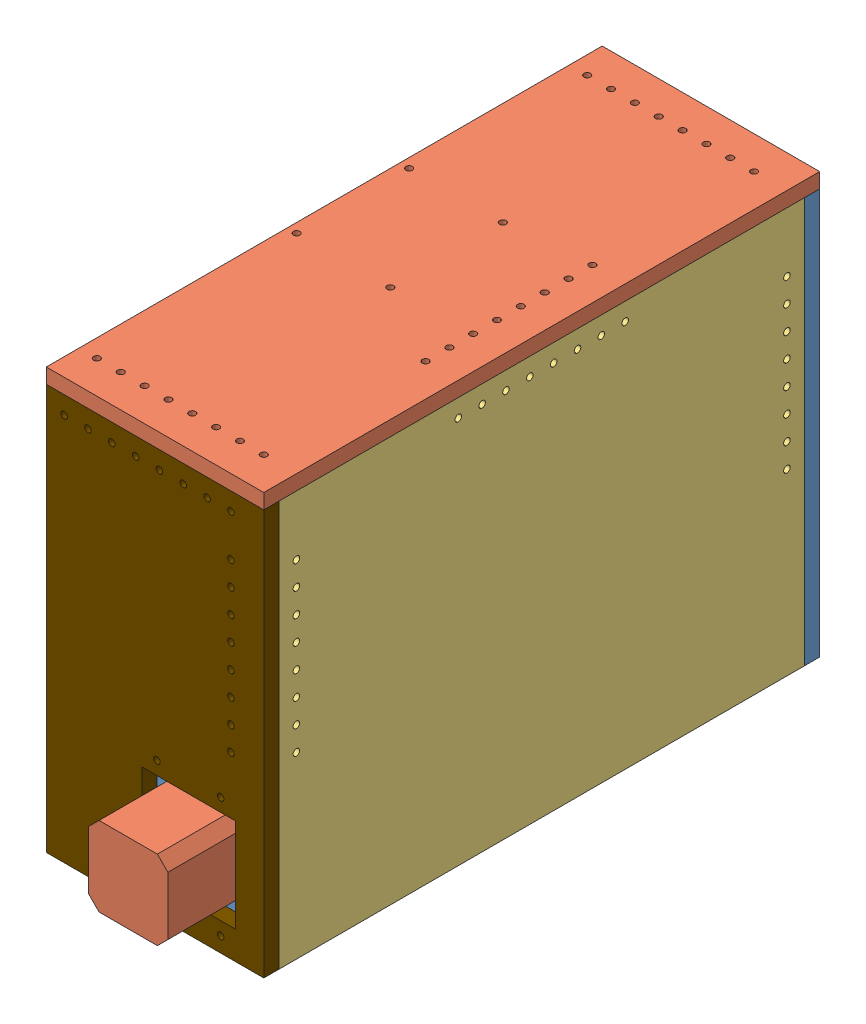
SolidWorks assembly MontagemPlataforma2, configuration Valor predeterminado. Lengths in mm.
Overall size (116 224.23 328.8).
33 component instances, 23 part files, 95 mates.
Components (placement in the parent):
- SuporteMotor-1: SuporteMotor [Valor predeterminado] at (-12.7116 1.7334 80) size (80 80 60)
- motorPasso-1: motorPasso [Valor predeterminado] at (-12.7116 1.7334 104.15) x (-1 0 0) z (0 -1 0) size (42.3 68.3 42.3)
- acoplador-1: acoplador [Valor predeterminado] at (-12.7116 1.7334 69.5) x (0.958308 -0.285739 0) z (0.285739 0.958308 0) size (19 25 19)
- ContraApoioMotor-1: ContraApoioMotor [Valor predeterminado] at (-12.7116 1.7334 -190.5) x (1 0 0) z (0 0 -1) size (80 80 39.5)
- plataforma-1: plataforma [Valor predeterminado] at (-58.7116 10.0216 -65.5) x (1 0 0) z (0 1 0) size (55 220 10)
- suportePlataforma-1: suportePlataforma [Valor predeterminado] at (-58.7116 20.0216 -65.5) x (0 0 1) z (0 1 0) size (190 55 65)
- guia200_5mm-1: guia200_5mm [Valor predeterminado] at (-12.7116 -25.2666 -55.25) x (1 0 0) z (0 -1 0) size (8 280.5 8)
- guia200_5mm-2: guia200_5mm [Valor predeterminado] at (-12.7116 28.7334 -55.25) x (1 0 0) z (0 -1 0) size (8 280.5 8)
- fusoTrapazoidal172_5mm-1: fusoTrapazoidal172_5mm [Valor predeterminado] at (-12.7116 1.7334 -69.25) x (-0.923728 -0.383049 0) z (-0.383049 0.923728 0) size (8.12 256.57 9.26)
- Rolamento-2: Rolamento [Valor predeterminado] at (-12.7116 1.7334 -185.5) size (47.5 27 13)
- RolamentoLinear-1: RolamentoLinear [Valor predeterminado] at (-12.7116 -25.2666 -128.1288) x (0.814438 -0.58025 0) z (0.58025 0.814438 0) size (15 24 15)
- RolamentoLinear-2: RolamentoLinear [Valor predeterminado] at (-12.7116 28.7334 -128.1288) x (1 0 0) z (0 1 0) size (15 24 15)
- corredor-1: corredor [Valor predeterminado] at (-11.7116 1.7334 -140.1288) x (-1 0 0) z (0 0 1) size (63.5 80 35)
- SensorFimdeCurso-1: SensorFimdeCurso [Valor predeterminado] at (-22.9616 27.9849 -179.2725) x (0 -1 0) z (-1 0 0) size (27.68 29.29 6)
- motorPasso para fuso-1: motorPasso para fuso [Valor predeterminado] at (-58.7116 156.8134 -65.5) x (0 0 1) z (1 0 0) size (42.3 44.3 42.3)
- fusoTrapazoidal100_8mm-1: fusoTrapazoidal100_8mm [Valor predeterminado] at (-58.7116 106.1634 -65.5) x (0.966852 0 -0.255339) z (0.255339 0 0.966852) size (8 56.69 8)
- Castanha-1: Castanha [Valor predeterminado] at (-58.7116 88.5216 -65.5) x (1 0 0) z (0 0 -1) size (22 15 22)
- box-1: box [Valor predeterminado] at (-46.3823 57.5484 4.885) size (240.83 240.83 240.83) (hidden)
- Castanha-2: Castanha [Valor predeterminado] at (-12.7116 1.7334 -130.1288) x (1 0 0) z (0 -1 0) size (22 15 22)
- RolamentoLinear-3: RolamentoLinear [Valor predeterminado] at (-58.7116 10.0216 34.5) size (15 24 15)
- RolamentoLinear-4: RolamentoLinear [Valor predeterminado] at (-58.7116 10.0216 -165.5) size (15 24 15)
- guia175.43_8mm-1: guia175.43_8mm [Valor predeterminado] at (-58.7116 69.8484 34.5) x (0.837169 0 0.546944) z (0 1 0) size (8 8 216.23)
- guia175.43_8mm-2: guia175.43_8mm [Valor predeterminado] at (-58.7116 69.8484 -165.5) x (1 0 0) z (0 -1 0) size (8 8 216.23)
- suporteFusoGuiaMotor-1: suporteFusoGuiaMotor [Valor predeterminado] at (-58.7116 172.9634 -65.5) x (0 0 1) z (0 -1 0) size (220 60 20)
- acrilico1-1: acrilico1 [Valor predeterminado] at (-12.7116 1.7334 85) x (-1 0 0) z (0 0 1) size (116 216.23 8)
- acrilico2-2: acrilico2 [Valor predeterminado] at (-30.7116 69.8484 -195.5) x (1 0 0) z (0 0 -1) size (116 216.23 8)
- acrilico3-1: acrilico3 [Valor predeterminado] at (-30.7116 185.9634 -55.25) x (1 0 0) z (0 -1 0) size (116 296.5 8)
- acrilico4-1: acrilico4 [Valor predeterminado] at (27.2884 69.8484 -55.25) x (0 0 1) z (-1 0 0) size (280.5 216.23 8)
- cantoneira-1: cantoneira [Valor predeterminado] at (19.2884 177.9634 -105.25) x (-1 0 0) z (0 0 1) size (15 15 100)
- cantoneira-2: cantoneira [Valor predeterminado] at (15.2884 177.9634 85) x (0 0 -1) z (-1 0 0) size (15 15 100)
- cantoneira-3: cantoneira [Valor predeterminado] at (-84.7116 177.9634 -195.5) x (0 0 1) z (1 0 0) size (15 15 100)
- cantoneira-4: cantoneira [Valor predeterminado] at (19.2884 151.7334 85.0065) x (-1 0 0) z (0 -1 0) size (15 15 100)
- cantoneira-5: cantoneira [Valor predeterminado] at (19.2884 151.7334 -195.5) x (0 0 1) z (0 -1 0) size (15 15 100)
Mates (geometry in assembly coordinates):
- Concêntrico1: concentric: cylinder of SuporteMotor-1 through (-12.7116 1.7334 59) axis (0 0 1) radius 11.02; cylinder of motorPasso-1 through (-12.7116 1.7334 81) axis (0 0 1) radius 11.025
- Coincidente1: coincident: plane of SuporteMotor-1 through (8.4384 22.8834 83) normal (-1 0 0); plane of motorPasso-1 through (8.4384 22.8834 83) normal (1 0 0)
- Coincidente2: coincident: plane of SuporteMotor-1 through (-12.7116 1.7334 83) normal (0 0 1); plane of motorPasso-1 through (-12.7116 1.7334 83) normal (0 0 -1)
- Concêntrico2: concentric: cylinder of motorPasso-1 through (-12.7116 1.7334 57) axis (0 0 1) radius 2.506; cylinder of acoplador-1 through (-12.7116 1.7334 57) axis (0 0 -1) radius 4
- Coincidente4: coincident: plane of motorPasso-1 through (-12.7116 1.7334 57) normal (0 0 -1); plane of acoplador-1 through (-12.7116 1.7334 57) normal (0 0 -1)
- Coincidente8: coincident: plane of SuporteMotor-1 through (-37.7116 41.7334 85) normal (0 1 0); plane of ContraApoioMotor-1 through (-37.7116 41.7334 -195.5) normal (0 1 0)
- Coincidente9: coincident: plane of SuporteMotor-1 through (-37.7116 -38.2666 85) normal (0 -1 0); plane of ContraApoioMotor-1 through (-37.7116 -38.2666 -195.5) normal (0 -1 0)
- Concêntrico7: concentric: cylinder of SuporteMotor-1 through (-12.7116 -25.2666 61) axis (0 0 1) radius 4; cylinder of guia200_5mm-1 through (-12.7116 -25.2666 85) axis (0 0 -1) radius 4
- Concêntrico8: concentric: cylinder of SuporteMotor-1 through (-12.7116 28.7334 61) axis (0 0 1) radius 4; cylinder of guia200_5mm-2 through (-12.7116 28.7334 85) axis (0 0 -1) radius 4
- Coincidente15: coincident: plane of SuporteMotor-1 through (-12.7116 1.7334 85) normal (0 0 1); plane of guia200_5mm-1 through (-12.7116 -25.2666 85) normal (0 0 1)
- Coincidente16: coincident: plane of SuporteMotor-1 through (-12.7116 1.7334 85) normal (0 0 1); plane of guia200_5mm-2 through (-12.7116 28.7334 85) normal (0 0 1)
- Concêntrico9: concentric: cylinder of acoplador-1 through (-12.7116 1.7334 57) axis (0 0 -1) radius 4; cylinder of fusoTrapazoidal172_5mm-1 through (-12.7116 1.7334 57) axis (0 0 -1) radius 4
- Coincidente17: coincident: plane of acoplador-1 through (-12.7116 1.7334 57) normal (0 0 -1); plane of fusoTrapazoidal172_5mm-1 through (-12.7116 1.7334 57) normal (0 0 1)
- Concêntrico10: concentric: cylinder of ContraApoioMotor-1 through (-12.7116 1.7334 -185.5) axis (0 0 -1) radius 4.5; cylinder of Rolamento-2 through (-12.7116 1.7334 -172.5) axis (0 0 -1) radius 7
- Concêntrico11: concentric: cylinder of ContraApoioMotor-1 through (-30.9616 1.7334 -185.5) axis (0 0 -1) radius 2.5; cylinder of Rolamento-2 through (-30.9616 1.7334 -181.5) axis (0 0 -1) radius 2.5
- Coincidente18: coincident: plane of ContraApoioMotor-1 through (-12.7116 1.7334 -185.5) normal (0 0 1); plane of Rolamento-2 through (-30.9616 1.7334 -185.5) normal (0 0 -1)
- Concêntrico12: concentric: cylinder of guia200_5mm-1 through (-12.7116 -25.2666 85) axis (0 0 -1) radius 4; cylinder of RolamentoLinear-1 through (-12.7116 -25.2666 -152.1288) axis (0 0 1) radius 4
- Coincidente19: coincident: plane of RolamentoLinear-1 through (-12.7116 -25.2666 -152.1288) normal (0 0 -1); plane of RolamentoLinear-2 through (-12.7116 28.7334 -152.1288) normal (0 0 -1)
- Coincidente20: coincident: plane of ContraApoioMotor-1 through (-27.7116 33.8734 -173.5) normal (0 -1 0); plane of SensorFimdeCurso-1 through (-24.2116 33.8734 -189.5) normal (0 1 0)
- Coincidente21: coincident: plane of ContraApoioMotor-1 through (-27.7116 32.3734 -173.5) normal (1 0 0); plane of SensorFimdeCurso-1 through (-27.7116 32.3734 -189.5) normal (-1 0 0)
- Coincidente22: coincident: plane of ContraApoioMotor-1 through (-12.7116 1.7334 -185.5) normal (0 0 1); plane of SensorFimdeCurso-1 through (-28.9616 35.1234 -185.5) normal (0 0 -1)
- Concêntrico17: concentric: cylinder of ? through (-58.7116 207.1531 -24) axis (0 -1 0) radius 9; cylinder of ? through (-58.7116 128.7561 -24) axis (0 -1 0) radius 9
- Concêntrico19: concentric: cylinder of motorPasso para fuso-1 through (-58.7116 203.6634 -65.5) axis (0 -1 0) radius 4; cylinder of fusoTrapazoidal100_8mm-1 through (-58.7116 133.6634 -65.5) axis (0 -1 0) radius 4
- Coincidente25: coincident: plane of motorPasso para fuso-1 through (-58.7116 133.6634 -65.5) normal (0 -1 0); plane of fusoTrapazoidal100_8mm-1 through (-58.7116 133.6634 -65.5) normal (0 1 0)
- Concêntrico21: concentric: cylinder of Castanha-1 through (-58.7116 122.4327 -7) axis (0 -1 0) radius 5.1; cylinder of ? through (-58.7116 103.9327 -7) axis (0 1 0) radius 5.105
- Paralelo10: parallel: cylinder of Castanha-1 through (-66.7001 122.4327 -6.5713) axis (0 -1 0) radius 1.75; cylinder of ? through (-66.8516 103.9327 -7) axis (0 1 0) radius 1.75
- Coincidente27: coincident: plane of Castanha-1 through (-58.7116 108.9327 -7) normal (0 -1 0); plane of ? through (-58.7116 108.9327 -7) normal (0 1 0)
- Concêntrico23: concentric: cylinder of ? through (-58.7116 103.9327 -37) axis (0 1 0) radius 7.5; cylinder of RolamentoLinear-3 through (-58.7116 122.9327 -37) axis (0 -1 0) radius 7.5
- Distância9: distance = 5 mm: plane of RolamentoLinear-3 through (-58.7116 98.9327 -37) normal (0 -1 0); plane of ? through (-58.7116 103.9327 -7) normal (0 -1 0)
- Concêntrico26: concentric: cylinder of ? through (-58.7116 103.9327 -24) axis (0 1 0) radius 4; cylinder of ? through (-58.7116 103.9327 -24) axis (0 -1 0) radius 4
- Coincidente31: coincident: plane of ? through (-58.7116 103.9327 -7) normal (0 -1 0); plane of ? through (-58.7116 103.9327 -24) normal (0 1 0)
- Concêntrico27: concentric: cylinder of ? through (-58.7116 103.9327 -24) axis (0 -1 0) radius 4; cylinder of ? through (-58.7116 48.9327 -24) axis (0 -1 0) radius 4
- Concêntrico29: concentric: cylinder of RolamentoLinear-3 through (-58.7116 122.9327 -37) axis (0 -1 0) radius 4; cylinder of ? through (-58.7116 79.0394 -37) axis (0 1 0) radius 4
- Coincidente35: coincident: plane of ? through (-58.7116 53.9327 -24) normal (0 -1 0); plane of ? through (-58.7116 53.9327 -24) normal (0 1 0)
- Concêntrico30: concentric: cylinder of fusoTrapazoidal172_5mm-1 through (-12.7116 1.7334 57) axis (0 0 -1) radius 4; cylinder of corredor-1 through (-12.7116 1.7334 -130.1288) axis (0 0 -1) radius 5.1
- Concêntrico32: concentric: cylinder of RolamentoLinear-2 through (-12.7116 28.7334 -152.1288) axis (0 0 1) radius 7.5; cylinder of corredor-1 through (-12.7116 28.7334 -130.1288) axis (0 0 -1) radius 7.5
- Coincidente40: coincident: plane of motorPasso-1 through (-12.7116 1.7334 125.3) normal (0 0 1); plane of box-1 through (-46.3823 57.5484 125.3) normal (0 0 1)
- Distância10: distance = 2 mm: plane of RolamentoLinear-1 through (-12.7116 -25.2666 -128.1288) normal (0 0 1); plane of corredor-1 through (-11.7116 1.7334 -130.1288) normal (0 0 1)
- Concêntrico34: concentric: cylinder of corredor-1 through (-12.7116 1.7334 -130.1288) axis (0 0 -1) radius 5.1; cylinder of Castanha-2 through (-12.7116 1.7334 -140.1288) axis (0 0 1) radius 5.1
- Concêntrico35: concentric: cylinder of corredor-1 through (-4.7116 1.7334 -155.0786) axis (0 0 1) radius 1.75; cylinder of Castanha-2 through (-4.7116 1.7334 -140.1288) axis (0 0 1) radius 1.75
- Coincidente42: coincident: plane of corredor-1 through (-11.7116 1.7334 -130.1288) normal (0 0 1); plane of Castanha-2 through (-12.7116 1.7334 -130.1288) normal (0 0 -1)
- Coincidente43: coincident: plane of plataforma-1 through (-58.7116 20.0216 -65.5) normal (0 1 0); plane of suportePlataforma-1 through (-58.7116 20.0216 -65.5) normal (0 -1 0)
- Concêntrico40: concentric: cylinder of suportePlataforma-1 through (-58.7116 85.0216 -65.5) axis (0 -1 0) radius 5; cylinder of fusoTrapazoidal100_8mm-1 through (-58.7116 133.6634 -65.5) axis (0 -1 0) radius 4
- Paralelo13: parallel: cylinder of suportePlataforma-1 through (-66.7116 57.0216 -65.5) axis (0 1 0) radius 1.75; cylinder of Castanha-1 through (-58.7116 98.5216 -73.5) axis (0 -1 0) radius 1.75
- Concêntrico44: concentric: circle of suportePlataforma-1; circle of Castanha-1
- Coincidente47: coincident: plane of suportePlataforma-1 through (-58.7116 85.0216 -65.5) normal (0 1 0); plane of Castanha-1 through (-58.7116 85.0216 -65.5) normal (0 -1 0)
- Concêntrico48: concentric: cylinder of suportePlataforma-1 through (-50.7116 57.0216 -65.5) axis (0 1 0) radius 1.75; cylinder of Castanha-1 through (-50.7116 98.5216 -65.5) axis (0 -1 0) radius 1.75
- Concêntrico49: concentric: cylinder of plataforma-1 through (-58.7116 10.0216 34.5) axis (0 1 0) radius 7.5; cylinder of RolamentoLinear-3 through (-58.7116 34.0216 34.5) axis (0 -1 0) radius 7.5
- Concêntrico50: concentric: cylinder of plataforma-1 through (-58.7116 10.0216 -165.5) axis (0 1 0) radius 7.5; cylinder of RolamentoLinear-4 through (-58.7116 34.0216 -165.5) axis (0 -1 0) radius 7.5
- Coincidente50: coincident: plane of plataforma-1 through (-58.7116 10.0216 -65.5) normal (0 -1 0); plane of RolamentoLinear-3 through (-58.7116 10.0216 34.5) normal (0 -1 0)
- Concêntrico51: concentric: cylinder of RolamentoLinear-3 through (-58.7116 34.0216 34.5) axis (0 -1 0) radius 4; cylinder of guia175.43_8mm-1 through (-58.7116 177.9634 34.5) axis (0 -1 0) radius 4
- Concêntrico52: concentric: cylinder of RolamentoLinear-4 through (-58.7116 34.0216 -165.5) axis (0 -1 0) radius 4; cylinder of guia175.43_8mm-2 through (-58.7116 -38.2666 -165.5) axis (0 1 0) radius 4
- Concêntrico57: concentric: circle of SuporteMotor-1; cylinder of acrilico1-1 through (-29.7116 -30.2666 93) axis (0 0 -1) radius 1.75
- Concêntrico58: concentric: cylinder of SuporteMotor-1 through (4.2884 33.7334 85) axis (0 0 -1) radius 1.75; cylinder of acrilico1-1 through (4.2884 33.7334 93) axis (0 0 -1) radius 1.75
- Coincidente57: coincident: plane of SuporteMotor-1 through (-12.7116 1.7334 85) normal (0 0 1); plane of acrilico1-1 through (-12.7116 1.7334 85) normal (0 0 -1)
- Concêntrico60: concentric: cylinder of ContraApoioMotor-1 through (-29.7116 -30.2666 -105.5) axis (0 0 -1) radius 1.75; cylinder of ? through (-29.7116 -30.2666 -115.5) axis (0 0 -1) radius 1.75
- Concêntrico61: concentric: cylinder of ContraApoioMotor-1 through (4.2884 33.7334 -105.5) axis (0 0 -1) radius 1.75; cylinder of ? through (4.2884 33.7334 -115.5) axis (0 0 -1) radius 1.75
- Coincidente59: coincident: plane of ContraApoioMotor-1 through (-12.7116 1.7334 -115.5) normal (0 0 -1); plane of ? through (-12.7116 1.7334 -115.5) normal (0 0 1)
- Coincidente68: coincident: plane of acrilico3-1 through (-30.7116 177.9634 -55.25) normal (0 -1 0); plane of acrilico4-1 through (19.2884 177.9634 -195.5) normal (0 1 0)
- Coincidente69: coincident: plane of acrilico3-1 through (27.2884 177.9634 93) normal (1 0 0); plane of acrilico4-1 through (27.2884 69.8484 -55.25) normal (1 0 0)
- Coincidente73: coincident: plane of acrilico1-1 through (-12.7116 1.7334 85) normal (0 0 -1); plane of cantoneira-2 through (-84.7116 177.9634 85) normal (0 0 1)
- Coincidente74: coincident: plane of acrilico3-1 through (-30.7116 177.9634 -55.25) normal (0 -1 0); plane of cantoneira-2 through (-84.7116 177.9634 85) normal (0 1 0)
- Coincidente77: coincident: plane of acrilico3-1 through (-30.7116 177.9634 -55.25) normal (0 -1 0); plane of cantoneira-3 through (15.2884 177.9634 -195.5) normal (0 1 0)
- Coincidente79: coincident: plane of acrilico4-1 through (19.2884 69.8484 -55.25) normal (-1 0 0); plane of cantoneira-4 through (19.2884 51.7334 85.0065) normal (1 0 0)
- Coincidente83: coincident: plane of acrilico4-1 through (19.2884 69.8484 -55.25) normal (-1 0 0); plane of cantoneira-5 through (19.2884 51.7334 -195.5) normal (1 0 0)
- Coincidente89: coincident: plane of acrilico2-2 through (-30.7116 69.8484 -203.5) normal (0 0 -1); plane of acrilico3-1 through (-88.7116 177.9634 -203.5) normal (0 0 -1)
- Coincidente90: coincident: plane of acrilico2-2 through (-30.7116 69.8484 -195.5) normal (0 0 1); plane of cantoneira-3 through (15.2884 177.9634 -195.5) normal (0 0 -1)
- Concêntrico62: concentric: circle of acrilico3-1; cylinder of cantoneira-3 through (-79.2116 273.9634 -186) axis (0 -1 0) radius 1.75
- Concêntrico63: concentric: circle of acrilico2-2; cylinder of cantoneira-3 through (-79.2116 168.4634 -291.5) axis (0 0 1) radius 1.75
- Coincidente91: coincident: plane of motorPasso para fuso-1 through (-79.8616 135.6634 -86.65) normal (0 0 -1); plane of suporteFusoGuiaMotor-1 through (-79.8616 167.9634 -86.65) normal (0 0 1)
- Coincidente92: coincident: plane of motorPasso para fuso-1 through (-79.8616 135.6634 -86.65) normal (-1 0 0); plane of suporteFusoGuiaMotor-1 through (-79.8616 167.9634 -86.65) normal (1 0 0)
- Concêntrico64: concentric: cylinder of plataforma-1 through (-81.2116 20.0216 24.5) axis (0 -1 0) radius 2; cylinder of suportePlataforma-1 through (-81.2116 20.0216 24.5) axis (0 1 0) radius 2
- Concêntrico65: concentric: cylinder of plataforma-1 through (-36.2116 20.0216 24.5) axis (0 -1 0) radius 2; cylinder of suportePlataforma-1 through (-36.2116 20.0216 24.5) axis (0 1 0) radius 2
- Concêntrico66: concentric: cylinder of acrilico4-1 through (17.2884 146.2334 -186) axis (1 0 0) radius 1.75; cylinder of cantoneira-5 through (115.2884 146.2334 -186) axis (-1 0 0) radius 1.75
- Concêntrico68: concentric: circle of cantoneira-5; circle of acrilico4-1
- Concêntrico69: concentric: circle of acrilico2-2; cylinder of cantoneira-5 through (9.7884 146.2334 -291.5) axis (0 0 1) radius 1.75
- Concêntrico70: concentric: cylinder of guia175.43_8mm-1 through (-58.7116 177.9634 34.5) axis (0 -1 0) radius 4; cylinder of suporteFusoGuiaMotor-1 through (-58.7116 157.9634 34.5) axis (0 1 0) radius 8
- Concêntrico71: concentric: cylinder of guia175.43_8mm-2 through (-58.7116 -38.2666 -165.5) axis (0 1 0) radius 4; cylinder of suporteFusoGuiaMotor-1 through (-58.7116 157.9634 -165.5) axis (0 1 0) radius 8
- Coincidente95: coincident: plane of guia175.43_8mm-1 through (-58.7116 177.9634 34.5) normal (0 1 0); plane of suporteFusoGuiaMotor-1 through (-58.7116 177.9634 -65.5) normal (0 1 0)
- Coincidente96: coincident: plane of guia175.43_8mm-2 through (-58.7116 177.9634 -165.5) normal (0 1 0); plane of suporteFusoGuiaMotor-1 through (-58.7116 177.9634 -65.5) normal (0 1 0)
- Concêntrico72: concentric: cylinder of suporteFusoGuiaMotor-1 through (-83.7116 177.9634 -35.5) axis (0 -1 0) radius 1.75; circle of acrilico3-1
- Concêntrico73: concentric: cylinder of suporteFusoGuiaMotor-1 through (-83.7116 177.9634 -95.5) axis (0 -1 0) radius 1.75; circle of acrilico3-1
- Coincidente98: coincident: plane of suporteFusoGuiaMotor-1 through (-58.7116 177.9634 -65.5) normal (0 1 0); plane of acrilico3-1 through (-30.7116 177.9634 -55.25) normal (0 -1 0)
- Coincidente99: coincident: plane of motorPasso para fuso-1 through (-58.7116 177.9634 -65.5) normal (0 1 0); plane of suporteFusoGuiaMotor-1 through (-58.7116 177.9634 -65.5) normal (0 1 0)
- Concêntrico74: concentric: cylinder of acrilico3-1 through (9.7884 277.9634 -99.75) axis (0 -1 0) radius 1.75; cylinder of cantoneira-1 through (9.7884 273.9634 -99.75) axis (0 -1 0) radius 1.75
- Concêntrico75: concentric: cylinder of acrilico4-1 through (119.2884 168.4634 -99.75) axis (-1 0 0) radius 1.75; cylinder of cantoneira-1 through (115.2884 168.4634 -99.75) axis (-1 0 0) radius 1.75
- Concêntrico76: concentric: cylinder of acrilico3-1 through (-79.2116 277.9634 75.5) axis (0 -1 0) radius 1.75; cylinder of cantoneira-2 through (-79.2116 273.9634 75.5) axis (0 -1 0) radius 1.75
- Concêntrico77: concentric: circle of acrilico3-1; cylinder of cantoneira-2 through (-66.4973 273.9634 75.5) axis (0 -1 0) radius 1.75
- Concêntrico78: concentric: cylinder of acrilico1-1 through (-79.2116 168.4634 185) axis (0 0 -1) radius 1.75; cylinder of cantoneira-2 through (-79.2116 168.4634 181) axis (0 0 -1) radius 1.75
- Concêntrico79: concentric: cylinder of acrilico1-1 through (-66.4973 168.4634 185) axis (0 0 -1) radius 1.75; cylinder of cantoneira-2 through (-66.4973 168.4634 181) axis (0 0 -1) radius 1.75
- Coincidente101: coincident: plane of plataforma-1 through (-58.7116 10.0216 -65.5) normal (0 -1 0); plane of RolamentoLinear-4 through (-58.7116 10.0216 -165.5) normal (0 -1 0)
- Concêntrico80: concentric: cylinder of guia200_5mm-2 through (-12.7116 28.7334 85) axis (0 0 -1) radius 4; cylinder of RolamentoLinear-2 through (-12.7116 28.7334 -152.1288) axis (0 0 1) radius 4
- Coincidente102: coincident: plane of acrilico2-2 through (-30.7116 69.8484 -203.5) normal (0 0 -1); plane of ? through (-88.7116 -48.2666 -203.5) normal (0 0 -1)
- Coincidente103: coincident: plane of acrilico4-1 through (19.2884 -38.2666 -195.5) normal (0 -1 0); plane of ? through (-30.7116 -38.2666 -55.25) normal (0 1 0)
- Coincidente104: coincident: plane of acrilico2-2 through (-88.7116 -38.2666 -203.5) normal (-1 0 0); plane of ? through (-88.7116 -48.2666 -203.5) normal (-1 0 0)
